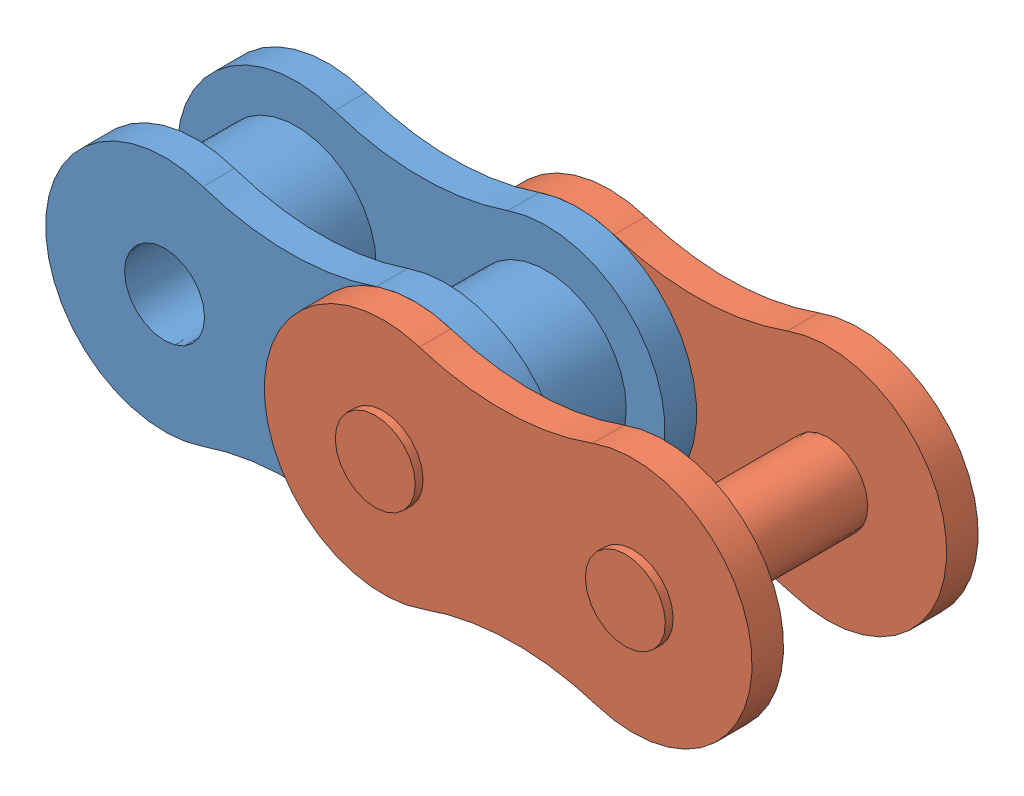
SolidWorks assembly PUTM-S-TR-GR-Chain-Links, configuration Domyślna. Lengths in mm.
Overall size (46.98 15.68 15.35).
2 component instances, 2 part files, 1 mates.
Components (placement in the parent):
- PUTM-S-TR-GR-Chain-Links-Inner-1: PUTM-S-TR-GR-Chain-Links-Inner [Domyślna] at (-11.2893 1.9082 25.79) size (30.96 15.09 10.35)
- PUTM-S-TR-GR-Chain-Links-Outer-1: PUTM-S-TR-GR-Chain-Links-Outer [Domyślna] at (4.5857 1.9082 23.79) x (0.999816 0.019157 0) z (0.019157 -0.999816 0) size (30.96 15.35 15.09)
Mates (geometry in assembly coordinates):
- Wspólnie1: coincident anti-aligned: plane of PUTM-E-DI-wewn-1 through (0.6169 13.5213 25.79) normal (0 0 -1); plane of PUTM-E-DI-zew-1 through (16.2672 13.7473 25.79) normal (0 0 1)
